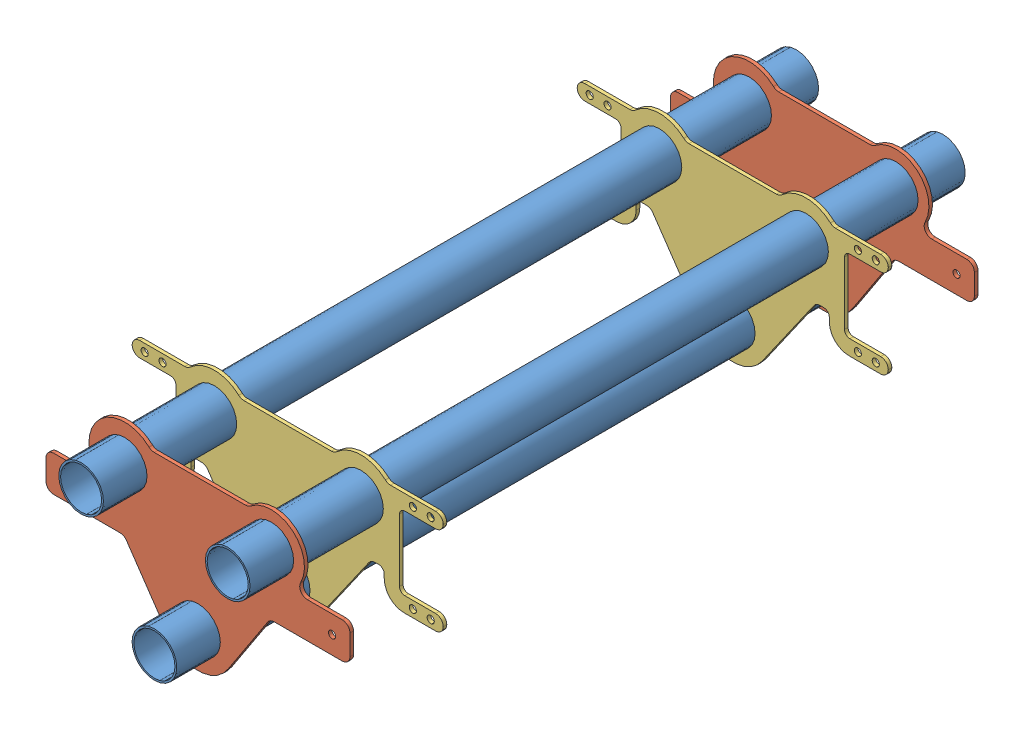
SolidWorks assembly Frame, configuration Default. Lengths in mm.
Overall size (174 100 400).
7 component instances, 3 part files, 9 mates.
Components (placement in the parent):
- frame_tube_1-1: frame_tube_1 [Default] at (41 0 0) size (25 25 400)
- hip_frame_2-1: hip_frame_2 [Default] at (0 -25 173.636) size (170 100 2)
- frame_tube_1-2: frame_tube_1 [Default] at (-41 0 0) size (25 25 400)
- hip_frame_1-1: hip_frame_1 [Default] at (0 -25 123.4577) size (174 100 2)
- frame_tube_1-3: frame_tube_1 [Default] at (0 -60 0) size (25 25 400)
- hip_frame_2-2: hip_frame_2 [Default] at (0 -25 -175.636) size (170 100 2)
- hip_frame_1-2: hip_frame_1 [Default] at (0 -25 -125.4577) size (174 100 2)
Mates (geometry in assembly coordinates):
- Concentric3: concentric aligned: cylinder of hip_frame_1-1 through (41 0 125.4577) axis (0 0 -1) radius 12.51; cylinder of frame_tube_1-1 through (41 0 200) axis (0 0 -1) radius 12.5
- Coincident5: coincident aligned: plane of frame_tube_1-1 through (41 0 200) normal (0 0 1); plane of frame_tube_1-3 through (0 -60 200) normal (0 0 1)
- Concentric6: concentric aligned: cylinder of frame_tube_1-1 through (41 0 200) axis (0 0 -1) radius 12.5; cylinder of hip_frame_2-1 through (41 0 175.636) axis (0 0 -1) radius 12.51
- Concentric5: concentric aligned: cylinder of frame_tube_1-2 through (-41 0 200) axis (0 0 -1) radius 12.5; cylinder of hip_frame_2-1 through (-41 0 175.636) axis (0 0 -1) radius 12.51
- Concentric7: concentric aligned: cylinder of frame_tube_1-3 through (0 -60 200) axis (0 0 -1) radius 12.5; cylinder of hip_frame_2-1 through (0 -60 175.636) axis (0 0 -1) radius 12.51
- Concentric2: concentric aligned: cylinder of hip_frame_1-1 through (-41 0 125.4577) axis (0 0 -1) radius 12.51; cylinder of frame_tube_1-2 through (-41 0 200) axis (0 0 -1) radius 12.5
- Coincident6: coincident aligned: plane of frame_tube_1-3 through (0 -60 200) normal (0 0 1); plane of frame_tube_1-2 through (-41 0 200) normal (0 0 1)
- Concentric4: concentric aligned: cylinder of hip_frame_1-1 through (0 -60 125.4577) axis (0 0 -1) radius 12.51; cylinder of frame_tube_1-3 through (0 -60 200) axis (0 0 -1) radius 12.5
- Coincident7: coincident aligned: plane of frame_tube_1-1 through (41 0 0) normal (0 1 0)
